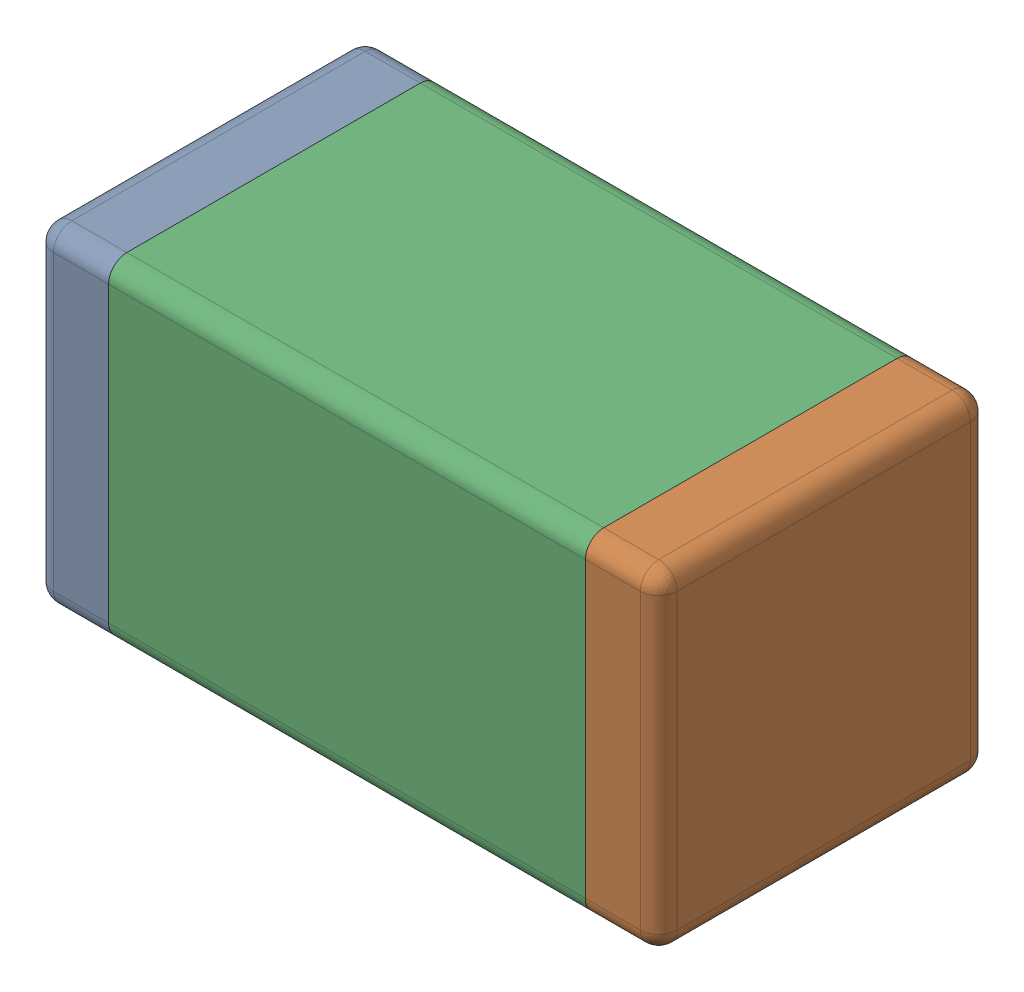
SolidWorks assembly 5943011504, configuration Default. Lengths in mm.
Overall size (1.7 0.9 0.9).
5 component instances, 3 part files, 0 mates.
Components (placement in the parent):
- Terminal_3-1: Terminal_3 [Default] at (-0.85 -0.45 0) size (1.7 0.9 0.9)
  - Open CASCADE STEP translator 6.8 6.1.1-1: Open CASCADE STEP translator 6.8 6.1.1 [Default] at origin size (0.2 0.9 0.9)
  - Open CASCADE STEP translator 6.8 6.1.2-1: Open CASCADE STEP translator 6.8 6.1.2 [Default] at origin size (0.2 0.9 0.9)
- Mid_Body-1: Mid_Body [Default] at (-0.85 -0.45 0) size (1.3 0.9 0.9)
  - Open CASCADE STEP translator 6.8 6.2.1-1: Open CASCADE STEP translator 6.8 6.2.1 [Default] at origin size (1.3 0.9 0.9)
